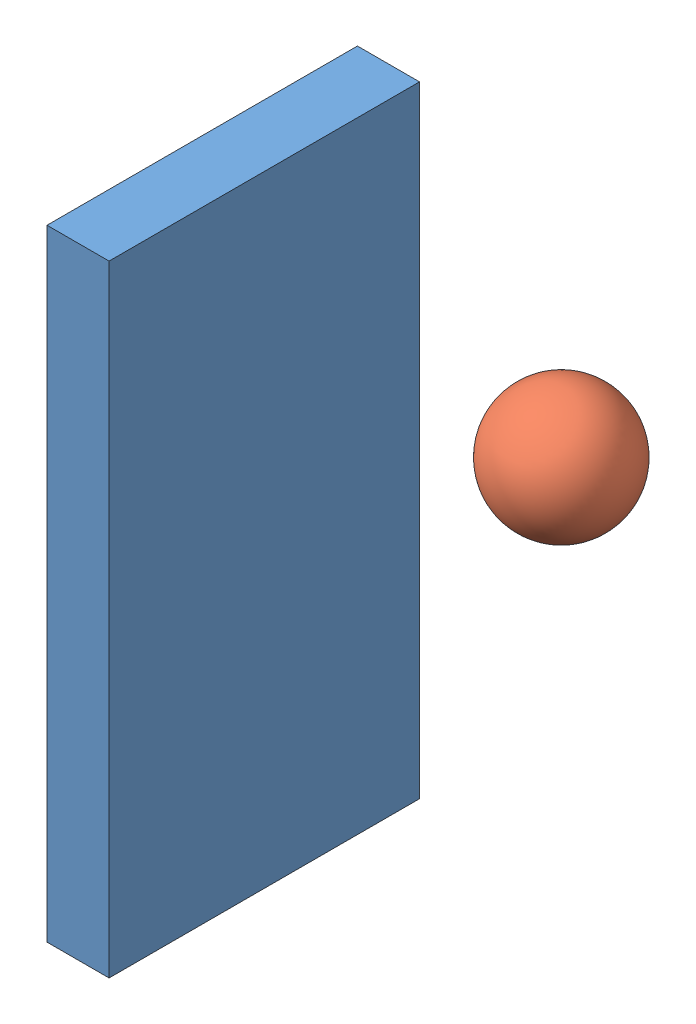
SolidWorks assembly Chute_bille, configuration Défaut. Lengths in mm.
Overall size (42.83 100 60).
2 component instances, 2 part files, 8 mates.
Components (placement in the parent):
- Bati^Chute_bille-1: Bati^Chute_bille [Défaut] at origin size (10 100 50) (virtual)
- Bille^Chute_bille-1: Bille^Chute_bille [Défaut] at origin size (20 42.82 20) (virtual)
Mates (geometry in assembly coordinates):
- Sur place1: in place: plane of ? through (0 0 0) normal (0 0 1); moOrthogonalPlaneRef_w of ? through (0 0 0) normal (0 1 0); plane of ? through (0 0 0) normal (1 0 0); unknown of ?
- Coïncidente1: coincident aligned: plane of Bati^Chute_bille-1; plane of assembly
- Coïncidente2: coincident aligned: plane of ? through (0 0 0) normal (0 1 0)
- Coïncidente3: coincident anti-aligned: plane of ? through (0 0 0) normal (1 0 0)
- Sur place2: in place: plane of ? through (0 0 0) normal (0 0 1); plane of ? through (0 0 0) normal (0 1 0); plane of ? through (0 0 0) normal (1 0 0); unknown of ?
- Coïncidente4: coincident aligned: plane of Bille^Chute_bille-1; plane of assembly
- Coïncidente5: coincident aligned: plane of ? through (0 0 0) normal (0 1 0)
- Coïncidente6: coincident anti-aligned: plane of ? through (0 0 0) normal (1 0 0)
